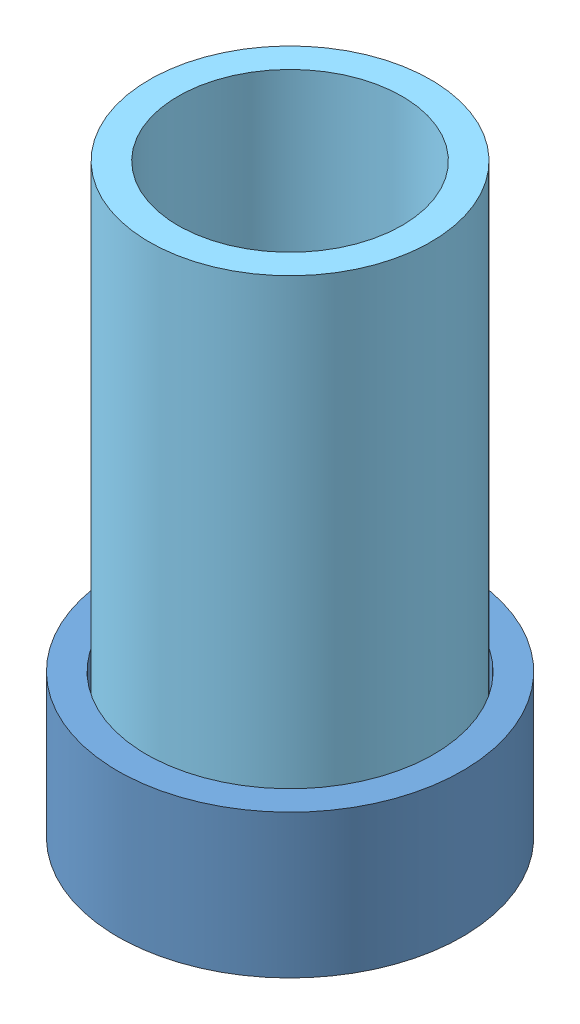
SolidWorks assembly smallPieceWeightAssem, configuration Default. Lengths in mm.
Overall size (69.17 102 69.17).
8 component instances, 5 part files, 14 mates.
Components (placement in the parent):
- hardBorderPart-1: hardBorderPart [Default] at (20.8312 21.6771 44.9341) size (60 25 60)
- insertSmall-1: insertSmall [Default] at (20.8312 21.6771 44.9341) x (-0.867505 0 0.497428) z (-0.497428 0 -0.867505) size (50 1 50)
- smallPiece-1: smallPiece [Default] at (14.6134 23.1771 34.0902) x (-0.837169 0 -0.546944) z (-0.546944 0 0.837169) size (8 1.5 8)
- smallPiece-2: smallPiece [Default] at (31.675 23.1771 38.7162) x (-0.992173 0 -0.124871) z (-0.124871 0 0.992173) size (8 1.5 8)
- smallPiece-3: smallPiece [Default] at (9.9874 23.1771 51.1519) x (0.993039 0 -0.117782) z (-0.117782 0 -0.993039) size (8 1.5 8)
- smallPiece-4: smallPiece [Default] at (27.0491 23.1771 55.7779) x (-0.249027 0 -0.968497) z (-0.968497 0 0.249027) size (8 1.5 8)
- yogaMat-1: yogaMat [Default] at (20.8312 23.6771 44.9341) x (-0.838578 0 -0.544782) z (-0.544782 0 0.838578) size (50 0.5 50)
- sandCyl-1: sandCyl [Default] at (20.8312 23.6771 44.9341) x (0.999585 0 0.028809) z (-0.028809 0 0.999585) size (49 100 49)
Mates (geometry in assembly coordinates):
- Concentric1: concentric aligned: circle of hardBorderPart-1; circle of insertSmall-1
- Coincident4: coincident aligned: plane of hardBorderPart-1 through (20.8312 21.6771 44.9341) normal (0 -1 0); plane of insertSmall-1 through (20.8312 21.6771 44.9341) normal (0 -1 0)
- Coincident5: coincident aligned: plane of insertSmall-1 through (20.8312 21.6771 44.9341) normal (0 -1 0); plane of smallPiece-1 through (14.6134 21.6771 34.0902) normal (0 -1 0)
- Concentric2: concentric anti-aligned: circle of insertSmall-1; circle of smallPiece-1
- Coincident6: coincident aligned: plane of insertSmall-1 through (20.8312 21.6771 44.9341) normal (0 -1 0); plane of smallPiece-2 through (31.675 21.6771 38.7162) normal (0 -1 0)
- Concentric3: concentric anti-aligned: circle of insertSmall-1; circle of smallPiece-2
- Coincident7: coincident aligned: plane of insertSmall-1 through (20.8312 21.6771 44.9341) normal (0 -1 0); plane of smallPiece-3 through (9.9874 21.6771 51.1519) normal (0 -1 0)
- Concentric4: concentric anti-aligned: circle of insertSmall-1; circle of smallPiece-3
- Coincident8: coincident aligned: plane of insertSmall-1 through (20.8312 21.6771 44.9341) normal (0 -1 0); plane of smallPiece-4 through (27.0491 21.6771 55.7779) normal (0 -1 0)
- Concentric5: concentric anti-aligned: circle of insertSmall-1; circle of smallPiece-4
- Coincident9: coincident anti-aligned: plane of smallPiece-3 through (9.9874 23.1771 51.1519) normal (0 1 0); plane of yogaMat-1 through (20.8312 23.1771 44.9341) normal (0 -1 0)
- Coincident10: coincident aligned: cylinder of hardBorderPart-1 through (20.8312 46.6771 44.9341) axis (0 -1 0) radius 25; circle of yogaMat-1
- Coincident11: coincident anti-aligned: plane of yogaMat-1 through (20.8312 23.6771 44.9341) normal (0 1 0); plane of sandCyl-1 through (20.8312 23.6771 44.9341) normal (0 -1 0)
- Concentric6: concentric aligned: circle of hardBorderPart-1; circle of sandCyl-1
